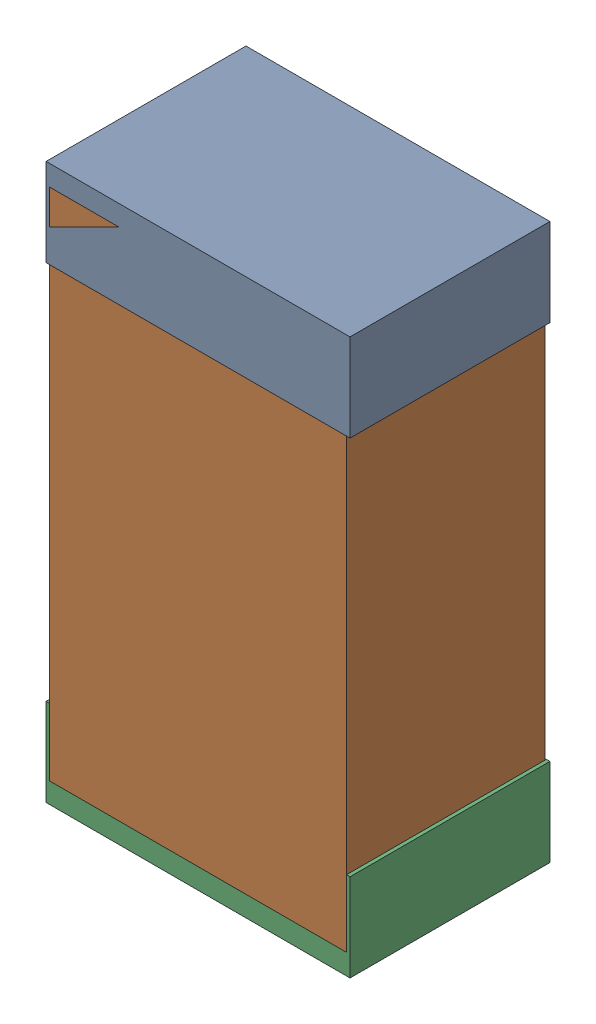
SolidWorks assembly R25Kanaloa_v2.0.0_Motor, configuration Default. Lengths in mm.
Overall size (1.3 2.38 0.85).
6 component instances, 2 part files, 0 mates.
Components (placement in the parent):
- 330415056-1: 330415056 [Default] at (38.354 94.726 -1.9574) size (1.3 0.38 0.85)
  - Extruded_2-1: Extruded_2 [Default] at origin size (1.3 0.38 0.85)
- 334787376-1: 334787376 [Default] at (38.354 93.726 -1.9524) size (1.27 2.2 0.85)
  - Extruded_16-1: Extruded_16 [Default] at origin size (1.27 2.2 0.85)
- 330415056-2: 330415056 [Default] at (38.354 92.726 -1.9574) size (1.3 0.38 0.85)
  - Extruded_2-1: Extruded_2 [Default] at origin size (1.3 0.38 0.85)
